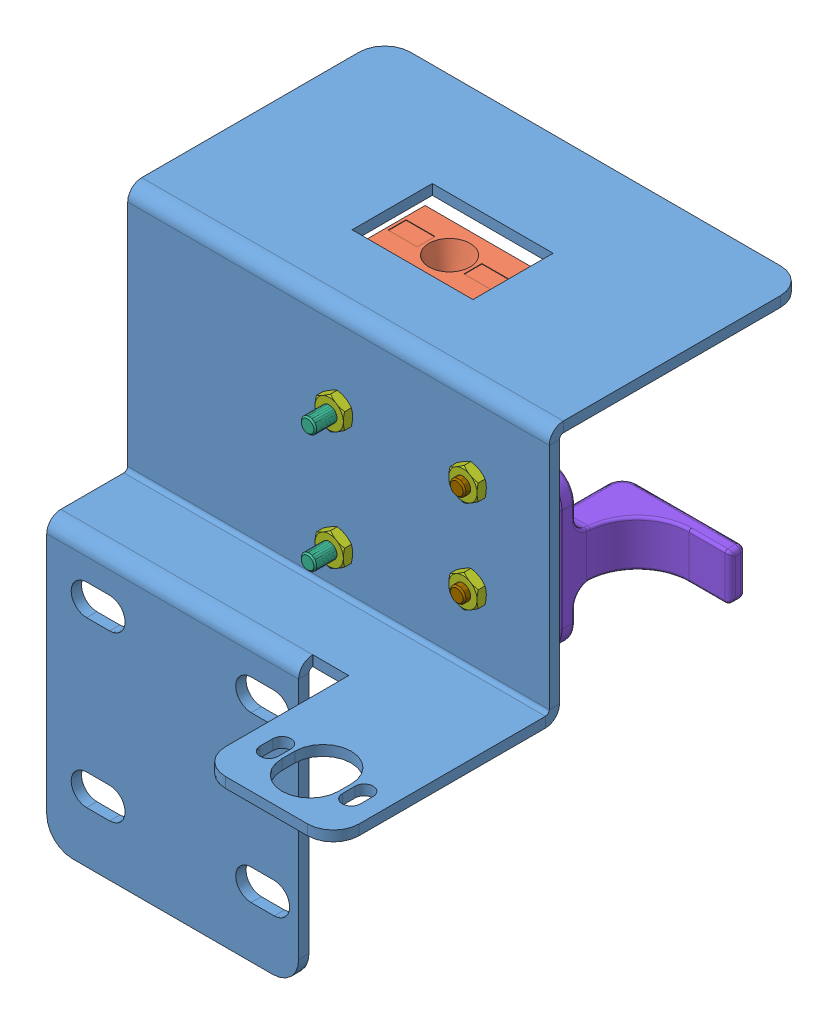
SolidWorks assembly T00006-000-R00, configuration Default. Lengths in mm.
Overall size (100 103 92).
18 component instances, 9 part files, 21 mates.
Components (placement in the parent):
- T00126-000-R02-1: T00126-000-R02 [Default] at (-76.7384 90.3354 70.4106) size (82 103 92)
- T00005-000-R00-1: T00005-000-R00 [Default] at (-79.4687 62.4093 14.8739) x (0 -1 0) z (1 0 0) size (53.8 27.95 21.5)
  - T00154-E00-R01-1: T00154-E00-R01 [Default] at (15.674 22.2087 43.7303) size (53.8 16.25 21.5)
  - T00172-000-R01-1: T00172-000-R01 [Default] at (22.774 33.8087 43.7303) size (39 12 21.5)
  - T00171-000-R01-1: T00171-000-R01 [Default] at (15.674 10.2087 43.7303) size (53.2 12 21.5)
  - T00173-000-R01-1: T00173-000-R01 [Default] at (25.474 28.1587 43.0803) size (6 10 6)
  - socket head cap screw_iso-1: socket head cap screw_iso [ISO 4762 M2 x 16 - 16C] at (40.074 37.8087 51.9803) x (0 -1 0) z (0 0 1) size (18 3.8 3.8)
  - socket head cap screw_iso-4: socket head cap screw_iso [ISO 4762 M2 x 16 - 16C] at (5.074 37.8087 51.9803) x (0 -1 0) z (0 0 1) size (18 3.8 3.8)
  - socket head cap screw_iso-5: socket head cap screw_iso [ISO 4762 M2 x 16 - 16C] at (40.074 37.8087 35.4803) x (0 -1 0) z (0 0 1) size (18 3.8 3.8)
- socket head cap screw_iso-1: socket head cap screw_iso [ISO 4762 M3 x 16 - 16C] at (-35.7384 58.3354 -6.3347) x (0 0 1) z (0 -1 0) size (19 5.5 5.5)
- socket head cap screw_iso-2: socket head cap screw_iso [ISO 4762 M3 x 16 - 16C] at (-35.7384 35.3354 -6.3347) x (0 0 1) z (0 -1 0) size (19 5.5 5.5)
- hex thin nut chamfered gradeab_iso-1: hex thin nut chamfered gradeab_iso [ISO - 4035 - M3 - C] at (-35.7384 35.3354 8.4653) size (5.5 6.35 1.8)
- hex thin nut chamfered gradeab_iso-2: hex thin nut chamfered gradeab_iso [ISO - 4035 - M3 - C] at (-35.7384 58.3354 8.4653) size (5.5 6.35 1.8)
- T00163-03D-R01-1: T00163-03D-R01 [Default] at (-4.7384 50.3354 4.6653) x (1 0 0) z (0 0 -1) size (38 30 18.2)
- socket countersunk head screw_iso-1: socket countersunk head screw_iso [ISO 10642 - M3 x 8 - 8C] at (-9.7384 59.3354 1.6553) x (0 0 1) z (0.923728 0.383049 0) size (8 5.54 5.54)
- socket countersunk head screw_iso-2: socket countersunk head screw_iso [ISO 10642 - M3 x 8 - 8C] at (-9.7384 41.3354 1.6553) x (0 0 1) z (0.923728 0.383049 0) size (8 5.54 5.54)
- hex thin nut chamfered gradeab_iso-5: hex thin nut chamfered gradeab_iso [ISO - 4035 - M3 - C] at (-9.7384 41.3354 8.4653) size (5.5 6.35 1.8)
- hex thin nut chamfered gradeab_iso-6: hex thin nut chamfered gradeab_iso [ISO - 4035 - M3 - C] at (-9.7384 59.3354 8.4653) size (5.5 6.35 1.8)
Mates (geometry in assembly coordinates):
- Coincident1: coincident: plane of T00126-000-R02-1 through (-76.7384 75.3354 4.6653) normal (0 0 -1); plane of T00005-000-R00-1/T00171-000-R01-1 through (-35.7384 46.7354 4.6653) normal (0 0 1)
- Coincident3: coincident: plane of T00126-000-R02-1 through (-76.7384 73.3354 -43.3347) normal (0 -1 0); plane of T00005-000-R00-1/T00154-E00-R01-1 through (-46.4884 73.3354 -20.9347) normal (0 1 0)
- Coincident4: coincident: plane of T00005-000-R00-1/T00171-000-R01-1 through (-35.7384 56.6354 -3.3347) normal (0 0 -1); plane of socket head cap screw_iso-1 through (-38.4884 58.3354 -3.3347) normal (0 0 1)
- Coincident5: coincident: plane of T00005-000-R00-1/T00171-000-R01-1 through (-35.7384 33.6354 -3.3347) normal (0 0 -1); plane of socket head cap screw_iso-2 through (-38.4884 35.3354 -3.3347) normal (0 0 1)
- Concentric1: concentric: cylinder of T00126-000-R02-1 through (-35.7384 58.3354 14.6653) axis (0 0 -1) radius 1.7; cylinder of socket head cap screw_iso-1 through (-35.7384 58.3354 -38.0847) axis (0 0 -1) radius 1.5
- Concentric2: concentric: cylinder of T00126-000-R02-1 through (-35.7384 35.3354 14.6653) axis (0 0 -1) radius 1.7; cylinder of socket head cap screw_iso-2 through (-35.7384 35.3354 -38.0847) axis (0 0 -1) radius 1.5
- Coincident7: coincident: plane of T00126-000-R02-1 through (-76.7384 75.3354 6.6653) normal (0 0 1); plane of hex thin nut chamfered gradeab_iso-2 through (-35.7384 61.5108 6.6653) normal (0 0 -1)
- Coincident8: coincident: plane of T00126-000-R02-1 through (-76.7384 75.3354 6.6653) normal (0 0 1); plane of hex thin nut chamfered gradeab_iso-1 through (-35.7384 38.5108 6.6653) normal (0 0 -1)
- Concentric3: concentric: cylinder of socket head cap screw_iso-2 through (-35.7384 35.3354 -38.0847) axis (0 0 -1) radius 1.5; cylinder of hex thin nut chamfered gradeab_iso-1 through (-35.7384 35.3354 6.6653) axis (0 0 1) radius 1.25
- Concentric4: concentric: cylinder of socket head cap screw_iso-1 through (-35.7384 58.3354 -38.0847) axis (0 0 -1) radius 1.5; cylinder of hex thin nut chamfered gradeab_iso-2 through (-35.7384 58.3354 6.6653) axis (0 0 1) radius 1.25
- Concentric5: concentric: cylinder of T00005-000-R00-1/T00171-000-R01-1 through (-35.7384 35.3354 -7.3347) axis (0 0 -1) radius 1.7; cylinder of socket head cap screw_iso-2 through (-35.7384 35.3354 -38.0847) axis (0 0 -1) radius 1.5
- Coincident9: coincident: plane of T00126-000-R02-1 through (-76.7384 75.3354 4.6653) normal (0 0 -1); plane of T00163-03D-R01-1 through (-9.7384 60.3354 4.6653) normal (0 0 1)
- Coincident10: coincident: plane of T00126-000-R02-1 through (5.2616 73.3354 6.6653) normal (1 0 0); plane of T00163-03D-R01-1 through (5.2616 60.3354 1.6653) normal (1 0 0)
- Width1: width: plane of T00126-000-R02-1 through (-76.7384 75.3354 -43.3347) normal (0 1 0); plane of T00126-000-R02-1 through (-76.7384 25.3354 -43.3347) normal (0 -1 0); plane of T00163-03D-R01-1 through (-9.7384 35.3354 1.6653) normal (0 -1 0); plane of T00163-03D-R01-1 through (-9.7384 65.3354 1.6653) normal (0 1 0)
- Coincident13: coincident: cone of T00163-03D-R01-1 through (-9.7384 59.3354 1.6653) axis (0 0 1); cone of socket countersunk head screw_iso-1 through (-9.7384 59.3354 2.2453) axis (0 0 1)
- Coincident14: coincident: cone of T00163-03D-R01-1 through (-9.7384 41.3354 1.6653) axis (0 0 1); cone of socket countersunk head screw_iso-2 through (-9.7384 41.3354 2.2453) axis (0 0 1)
- Concentric6: concentric: cylinder of socket countersunk head screw_iso-2 through (-9.7384 41.3354 1.6553) axis (0 0 -1) radius 1.5; cylinder of ? through (-9.7384 41.3354 6.0675) axis (0 0 1) radius 2.1
- Coincident15: coincident: plane of T00126-000-R02-1 through (-76.7384 75.3354 6.6653) normal (0 0 1); plane of hex thin nut chamfered gradeab_iso-6 through (-9.7384 62.5108 6.6653) normal (0 0 -1)
- Coincident16: coincident: plane of T00126-000-R02-1 through (-76.7384 75.3354 6.6653) normal (0 0 1); plane of hex thin nut chamfered gradeab_iso-5 through (-9.7384 44.5108 6.6653) normal (0 0 -1)
- Concentric7: concentric: cylinder of socket countersunk head screw_iso-2 through (-9.7384 41.3354 1.6553) axis (0 0 -1) radius 1.5; cylinder of hex thin nut chamfered gradeab_iso-5 through (-9.7384 41.3354 6.6653) axis (0 0 1) radius 1.25
- Concentric8: concentric: cylinder of socket countersunk head screw_iso-1 through (-9.7384 59.3354 1.6553) axis (0 0 -1) radius 1.5; cylinder of hex thin nut chamfered gradeab_iso-6 through (-9.7384 59.3354 6.6653) axis (0 0 1) radius 1.25
